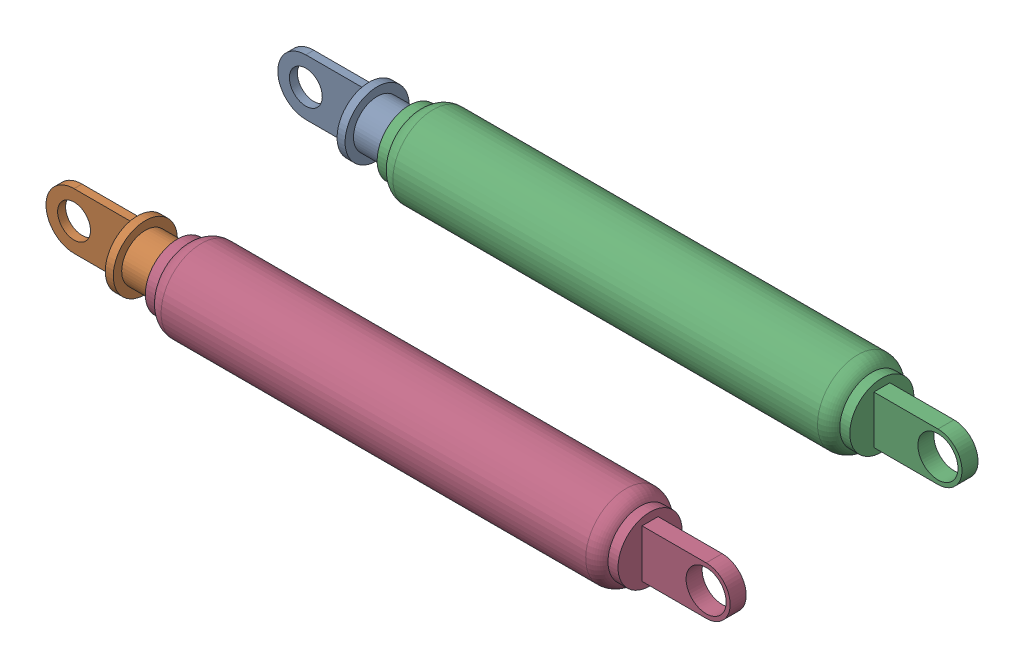
SolidWorks assembly Assem_springs, configuration Default. Lengths in mm.
Overall size (85.9 10.06 39).
4 component instances, 2 part files, 7 mates.
Components (placement in the parent):
- Axel-1: Axel [Default] at (-1.5 0 0) x (-1 0 0) z (0 -1 0) size (65.9 8 8)
- Axel-2: Axel [Default] at (-1.5 0 28.9334) x (-1 0 0) z (0 -1 0) size (65.9 8 8)
- Spring-1: Spring [Default] at origin size (70 10.06 10.06)
- Spring-2: Spring [Default] at (0 0 28.9334) size (70 10.06 10.06)
Mates (geometry in assembly coordinates):
- Coincident3: coordinate: point of 1. spring-1
- LimitDistance1: limit distance = -20 mm anti-aligned: plane of 1. axel-1 through (20.5 0 0) normal (1 0 0); plane of 1. spring-1 through (0.5 0 0) normal (-1 0 0)
- Coincident4: coincident anti-aligned: plane of 1. axel-1 through (-1.5 0 0) normal (0 0 -1); plane of 1. spring-1 through (0 0 0) normal (0 0 1)
- Coincident5: coincident anti-aligned: plane of 1. axel-1 through (-1.5 0 0) normal (0 -1 0); plane of 1. spring-1 through (0 0 0) normal (0 1 0)
- Coincident6: coincident aligned: line of 1. axel-1 through (-41.8984 0 -10.9013) axis (0 0 1); line of 1. axel-2 through (-41.8984 0 18.0322) axis (0 0 1)
- Concentric1: concentric aligned: cylinder of 1. axel-2 through (20.5 0 28.9334) axis (-1 0 0) radius 2.95; cylinder of 1. spring-2 through (-29.5 0 28.9334) axis (-1 0 0) radius 3
- Coincident7: coincident aligned: line of 1. spring-1 through (37.5 0 3.2933) axis (0 0 -1); line of 1. spring-2 through (37.5 0 32.2267) axis (0 0 -1)
